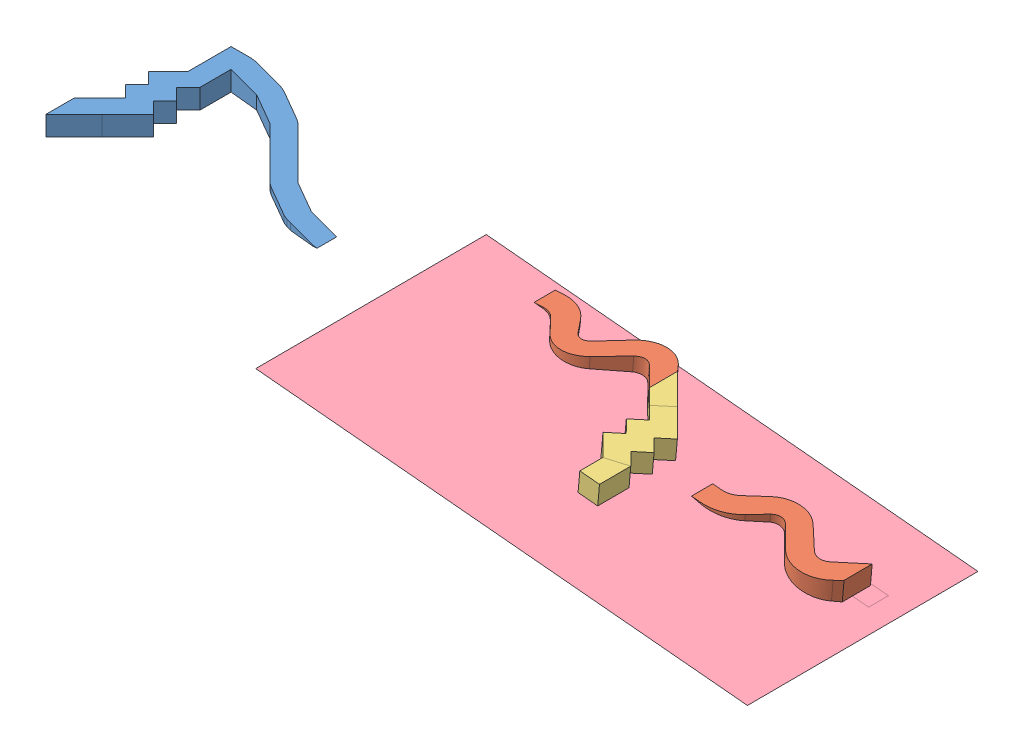
SolidWorks assembly Assem1, configuration Default. Lengths in mm.
Overall size (23791.53 2414.23 7275.64).
6 component instances, 4 part files, 7 mates.
Components (placement in the parent):
- arena1-1: arena1 [Default] at (-7892.7873 310.8398 -2713.9515) x (1 0 0) z (0 0 -1) size (7639.44 600 4593.46)
- slope 2-1: slope 2 [Default] at (-1180.2872 -92.4605 -4498.2256) x (0.995678 -0.092873 0) z (0.000361 0.003875 -0.999992) size (4165.38 600 1589.5)
- slope 2-2: slope 2 [Default] at (6646.9565 -826.9216 -3382.0542) x (0.995678 -0.092873 0) z (-0.000361 -0.003875 0.999992) size (4165.38 600 1589.5)
- river-1: river [Default] at (7421.6933 -896.1461 -4159.8658) x (0.995678 -0.092873 0) z (-0.000361 -0.003875 0.999992) size (1629.25 600 3993.46)
- Assem1^Assem1-1: Assem1^Assem1 [Default] at (-7675.8729 -83.1677 -6037.3692) x (0.995678 -0.092873 0) z (-0.000361 -0.003875 0.999992) size (15000 0 7000) (virtual)
  - base-1: base [Default] at origin size (15000 0 7000)
Mates (geometry in assembly coordinates):
- Coincident4: coincident: line of slope 2-2 through (440.7878 -255.9388 -1359.1142) axis (-0.995678 0.092873 0); line of river-1 through (440.7878 -255.9388 -1359.1142) axis (-0.995678 0.092873 0)
- Coincident6: coincident: point of slope 2-2; point of river-1
- Coincident8: coincident anti-aligned: line of slope 2-1 through (-1179.9784 -89.15 -5352.5491) axis (-0.000361 -0.003875 0.999992); line of river-1 through (-1180.2872 -92.4605 -4498.2256) axis (0.000361 0.003875 -0.999992)
- Coincident9: coincident: point of slope 2-1; point of river-1
- Coincident11: coincident: point of Assem1^Assem1-1/base-1; point of slope 2-2
- Parallel5: parallel: line of Assem1^Assem1-1/base-1 through (6591.2329 -1424.3238 -3384.3893) axis (0.000361 0.003875 -0.999992); line of slope 2-2 through (-156.6189 -200.2148 -1359.1142) axis (-0.000361 -0.003875 0.999992)
- Coincident12: coincident anti-aligned: plane of slope 2-1 through (-2111.4484 -606.6517 -4897.9396) normal (-0.092873 -0.99567 -0.003892); plane of Assem1^Assem1-1/base-1 through (-7675.8729 -83.1677 -6037.3692) normal (0.092873 0.99567 0.003892)
